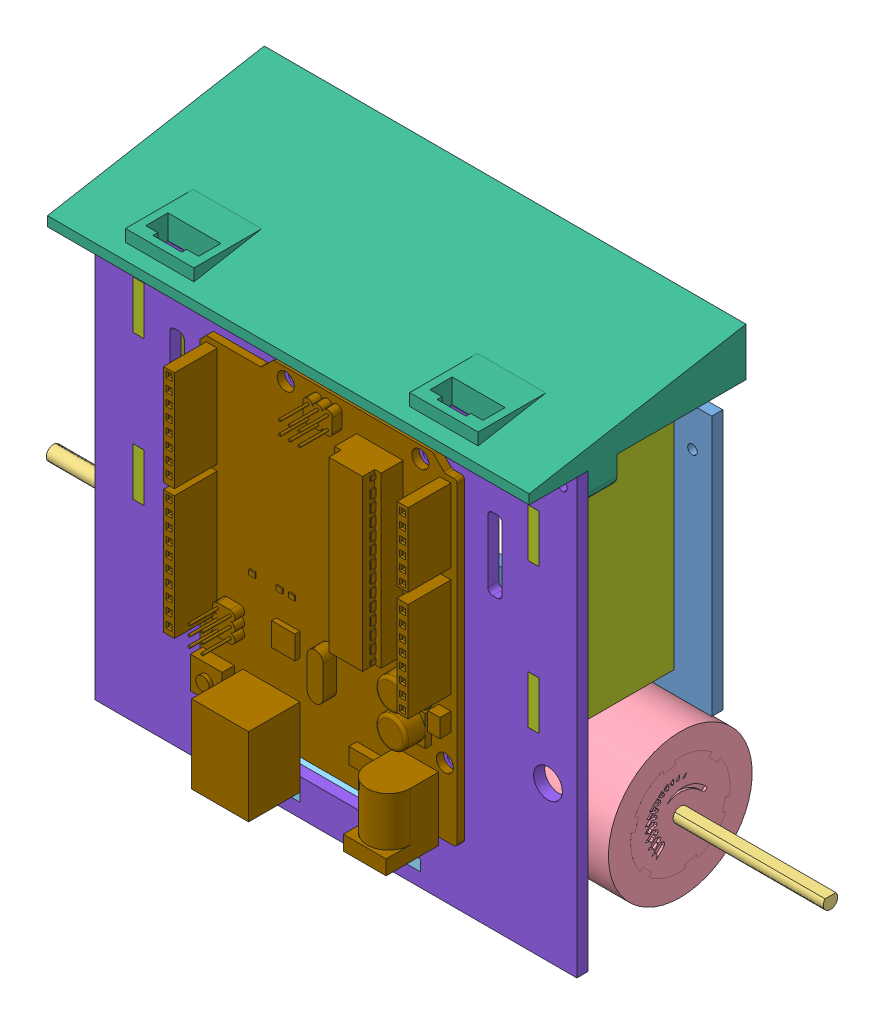
SolidWorks assembly Sumo Assembly Kit1, configuration Default. Lengths in mm.
Overall size (161.3 102.97 55.54).
12 component instances, 9 part files, 30 mates.
Components (placement in the parent):
- Bottom Plate 2.3mm V2 Kit 1-1: Bottom Plate 2.3mm V2 Kit 1 [Default] at (-30.1182 104.5043 79.842) size (100 90 2.3)
- Dual Motor Mount V3.1-1: Dual Motor Mount V3.1 [Default] at (44.8815 45.3793 82.142) x (-1 0 0) z (0 1 0) size (50 16.9 25.5)
- FingerTech_Gold_Spark_16mm_motor-1: FingerTech_Gold_Spark_16mm_motor [Default] at (-11.7139 32.6293 88.142) size (79.35 17.99 15.58)
- FingerTech_Gold_Spark_16mm_motor-2: FingerTech_Gold_Spark_16mm_motor [Default] at (51.4769 32.6293 88.142) x (-1 0 0) z (0 0 1) size (79.35 17.99 15.58)
- MiniSumo_wheel_1125-1: MiniSumo_wheel_1125 [Default] at (-29.5885 32.6293 88.142) size (21.59 29.84 29.84)
- MiniSumo_wheel_1125-2: MiniSumo_wheel_1125 [Default] at (69.3515 32.6293 88.142) x (-1 0 0) z (0 0.727763 0.685828) size (21.59 29.84 29.84)
- Back Bracket 2.3mm-1: Back Bracket 2.3mm [Default] at (-7.1182 16.6571 106.642) x (1 0 0) z (0 1 0) size (54 30.3 2.3)
- 3D Ramp Kit 1-1: 3D Ramp Kit 1 [Default] at (-30.1182 104.5043 75.042) x (0 1 0) z (1 0 0) size (16 45 100)
- Side Bracket 2.3mm V2 Kit 1-1: Side Bracket 2.3mm V2 Kit 1 [Default] at (-22.9654 52.0043 79.842) x (0 1 0) z (1 0 0) size (45 30.3 2.3)
- Side Bracket 2.3mm V2 Kit 1-2: Side Bracket 2.3mm V2 Kit 1 [Default] at (59.0346 52.0043 79.842) x (0 1 0) z (1 0 0) size (45 30.3 2.3)
- Top Plate 2.3mm V2 Kit 1-1: Top Plate 2.3mm V2 Kit 1 [Default] at (-30.1182 104.5043 107.842) size (100 90 2.3)
- uploads-b4-22-56-eb-53-Arduino.ipt1-1: uploads-b4-22-56-eb-53-Arduino.ipt1 [Default] at (46.526 93.0746 110.142) x (-0.000111 1 0) z (1 0.000111 0) size (74.93 14.99 53.34)
Mates (geometry in assembly coordinates):
- Coincident1: coincident anti-aligned: plane of Bottom Plate 2.3mm V2 Kit 1-1 through (-30.1182 104.5043 82.142) normal (0 0 1); plane of Dual Motor Mount V3.1-1 through (44.8815 45.3793 82.142) normal (0 0 -1)
- Concentric1: concentric anti-aligned: circle of Bottom Plate 2.3mm V2 Kit 1-1; circle of Dual Motor Mount V3.1-1
- Concentric2: concentric anti-aligned: circle of Bottom Plate 2.3mm V2 Kit 1-1; circle of Dual Motor Mount V3.1-1
- Concentric7: concentric aligned: circle of Dual Motor Mount V3.1-1; circle of FingerTech_Gold_Spark_16mm_motor-1
- Coincident6: coincident anti-aligned: plane of Dual Motor Mount V3.1-1 through (16.8815 32.6293 88.142) normal (-1 0 0); plane of FingerTech_Gold_Spark_16mm_motor-1 through (16.8815 30.7652 90.0061) normal (1 0 0)
- Parallel2: parallel anti-aligned: plane of Bottom Plate 2.3mm V2 Kit 1-1 through (-30.1182 104.5043 82.142) normal (0 0 1); plane of FingerTech_Gold_Spark_16mm_motor-1 through (-9.8352 36.8293 82.042) normal (0 0 -1)
- Concentric8: concentric aligned: circle of Dual Motor Mount V3.1-1; circle of FingerTech_Gold_Spark_16mm_motor-2
- Coincident8: coincident anti-aligned: plane of Dual Motor Mount V3.1-1 through (22.8815 32.6293 88.142) normal (1 0 0); plane of FingerTech_Gold_Spark_16mm_motor-2 through (22.8815 34.4934 90.0061) normal (-1 0 0)
- Parallel3: parallel anti-aligned: plane of Bottom Plate 2.3mm V2 Kit 1-1 through (-30.1182 104.5043 82.142) normal (0 0 1); plane of FingerTech_Gold_Spark_16mm_motor-2 through (49.5982 28.4293 82.042) normal (0 0 -1)
- Concentric9: concentric anti-aligned: circle of FingerTech_Gold_Spark_16mm_motor-2; circle of MiniSumo_wheel_1125-2
- Coincident10: coincident anti-aligned: plane of FingerTech_Gold_Spark_16mm_motor-2 through (63.0015 40.447 80.3243) normal (1 0 0); plane of MiniSumo_wheel_1125-2 through (63.0015 45.1198 87.7715) normal (-1 0 0)
- Concentric10: concentric anti-aligned: circle of FingerTech_Gold_Spark_16mm_motor-1; circle of MiniSumo_wheel_1125-1
- Coincident11: coincident anti-aligned: plane of FingerTech_Gold_Spark_16mm_motor-1 through (-23.2385 24.8116 80.3243) normal (-1 0 0); plane of MiniSumo_wheel_1125-1 through (-23.2385 23.7932 96.978) normal (1 0 0)
- Coincident12: coincident anti-aligned: plane of Bottom Plate 2.3mm V2 Kit 1-1 through (-30.1182 104.5043 82.142) normal (0 0 1); plane of Back Bracket 2.3mm-1 through (27.3818 17.3543 82.142) normal (0 0 -1)
- Coincident13: coincident anti-aligned: plane of Bottom Plate 2.3mm V2 Kit 1-1 through (37.3818 19.6543 79.842) normal (0 -1 0); plane of Back Bracket 2.3mm-1 through (-7.1182 19.6543 106.642) normal (0 1 0)
- Coincident14: coincident anti-aligned: plane of Bottom Plate 2.3mm V2 Kit 1-1 through (2.3818 17.3543 79.842) normal (1 0 0); plane of Back Bracket 2.3mm-1 through (2.3818 17.3543 79.842) normal (-1 0 0)
- Coincident15: coincident anti-aligned: plane of Bottom Plate 2.3mm V2 Kit 1-1 through (-30.1182 104.5043 82.142) normal (0 0 1); plane of 3D Ramp Kit 1-1 through (-17.6182 98.5043 82.142) normal (0 0 -1)
- Coincident16: coincident aligned: circle of Bottom Plate 2.3mm V2 Kit 1-1; circle of 3D Ramp Kit 1-1
- Coincident17: coincident aligned: circle of Bottom Plate 2.3mm V2 Kit 1-1; circle of 3D Ramp Kit 1-1
- Coincident19: coincident anti-aligned: plane of Bottom Plate 2.3mm V2 Kit 1-1 through (-19.9682 94.5043 79.842) normal (-1 0 0); plane of Side Bracket 2.3mm V2 Kit 1-1 through (-19.9682 52.0043 79.842) normal (1 0 0)
- Coincident25: coincident anti-aligned: plane of Bottom Plate 2.3mm V2 Kit 1-1 through (59.7318 94.5043 79.842) normal (1 0 0); plane of Side Bracket 2.3mm V2 Kit 1-2 through (59.7318 52.0043 79.842) normal (-1 0 0)
- Coincident27: coincident anti-aligned: plane of Back Bracket 2.3mm-1 through (12.3818 17.3543 107.842) normal (0 0 1); plane of Top Plate 2.3mm V2 Kit 1-1 through (-30.1182 104.5043 107.842) normal (0 0 -1)
- Coincident28: coincident anti-aligned: plane of Back Bracket 2.3mm-1 through (-7.1182 19.6543 106.642) normal (0 1 0); plane of Top Plate 2.3mm V2 Kit 1-1 through (2.3818 19.6543 107.842) normal (0 -1 0)
- Coincident30: coincident anti-aligned: plane of Back Bracket 2.3mm-1 through (37.3818 17.3543 110.142) normal (1 0 0); plane of Top Plate 2.3mm V2 Kit 1-1 through (37.3818 17.3543 107.842) normal (-1 0 0)
- Coincident31: coincident anti-aligned: plane of Bottom Plate 2.3mm V2 Kit 1-1 through (-30.1182 104.5043 82.142) normal (0 0 1); plane of Side Bracket 2.3mm V2 Kit 1-1 through (-22.2682 74.5043 82.142) normal (0 0 -1)
- Coincident33: coincident anti-aligned: plane of Bottom Plate 2.3mm V2 Kit 1-1 through (-22.2682 94.5043 79.842) normal (0 -1 0); plane of Side Bracket 2.3mm V2 Kit 1-1 through (-22.2682 94.5043 79.842) normal (0 1 0)
- Coincident34: coincident anti-aligned: plane of Bottom Plate 2.3mm V2 Kit 1-1 through (-30.1182 104.5043 82.142) normal (0 0 1); plane of Side Bracket 2.3mm V2 Kit 1-2 through (59.7318 74.5043 82.142) normal (0 0 -1)
- Coincident35: coincident anti-aligned: plane of Side Bracket 2.3mm V2 Kit 1-2 through (59.7318 94.5043 110.142) normal (0 1 0); plane of Top Plate 2.3mm V2 Kit 1-1 through (59.7318 94.5043 107.842) normal (0 -1 0)
- Coincident36: coincident anti-aligned: plane of Top Plate 2.3mm V2 Kit 1-1 through (-30.1182 104.5043 110.142) normal (0 0 1); plane of uploads-b4-22-56-eb-53-Arduino.ipt1-1 through (19.9882 60.6246 110.142) normal (0 0 -1)
- Concentric11: concentric aligned: circle of Top Plate 2.3mm V2 Kit 1-1; circle of uploads-b4-22-56-eb-53-Arduino.ipt1-1
